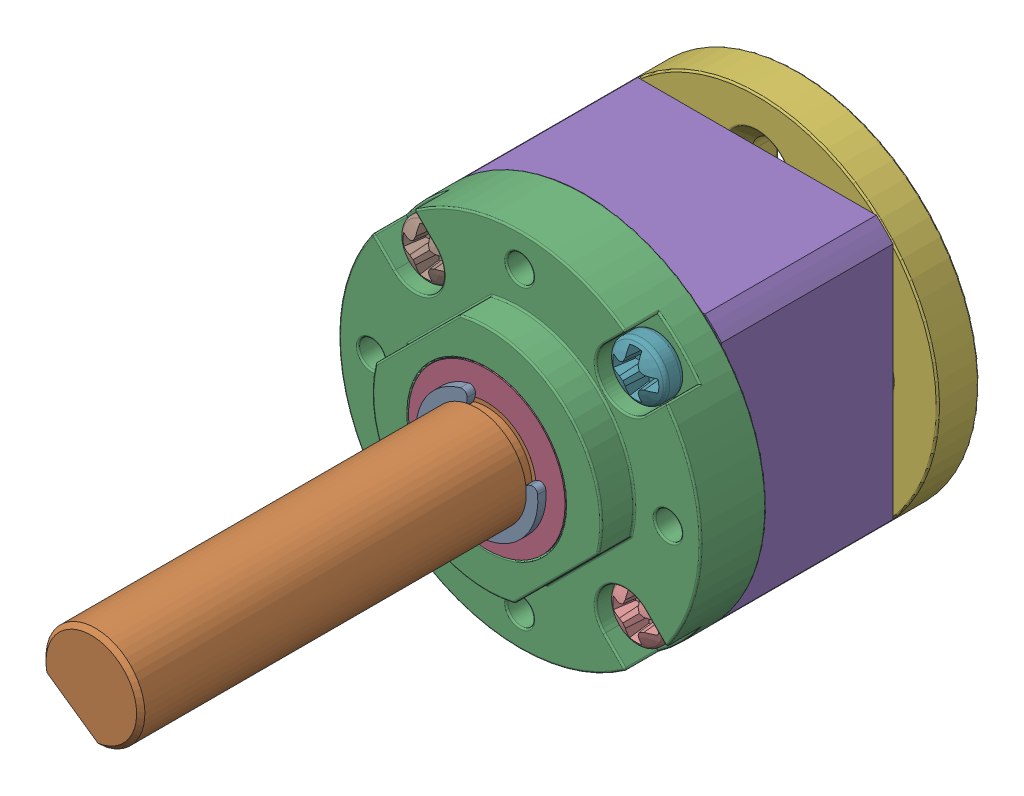
SolidWorks assembly DartBox V2 Drive 6mm Output.stp, configuration Default. Lengths in mm.
Overall size (21.95 21.95 42.9).
13 component instances, 7 part files, 0 mates.
Components (placement in the parent):
- Ring Gear.stp-1: Ring Gear.stp [Default] at (-10.101 0.0152 -54.1116) x (0 -1 0) z (0 0 1) size (21.95 21.95 40.4)
  - Front Plate.stp-1: Front Plate.stp [Default] at (0.0152 10.101 56.6116) x (0 1 0) z (1 0 0) size (21.95 30.5 21.95)
    - Shaft.stp-1: Shaft.stp [Default] x (-0.819152 0 -0.573576) z (0.573576 0 -0.819152) size (7.4 30.3 6.7)
      - Retaining Ring.stp-1: Retaining Ring.stp [Default] at (0 16.65 0) x (-1 0 0) z (0 -1 0) size (7.4 6.16 0.5)
      - Shaft-0.stp-1: Shaft-0.stp [Default] at origin size (6 30.3 6)
    - Front Plate-1.stp-1: Front Plate-1.stp [Default] at origin size (21.95 6.5 21.95)
    - Front Plate-2.stp-1: Front Plate-2.stp [Default] at origin size (9.5 6 9.5)
  - Ring Gear Body.stp-1: Ring Gear Body.stp [Default] at (0.0152 10.101 56.6116) x (0 1 0) z (1 0 0) size (16.5 10.4 16.5)
- Motor Mount Plate.stp-1: Motor Mount Plate.stp [Default] at (0 0 2.5) x (1 0 0) z (0 -1 0) size (21.95 3.5 21.95)
- Screws M2 x 14mm.stp-1: Screws M2 x 14mm.stp [Default] at (6.364 6.364 0.9) size (3.4 3.4 15.61)
- Screws M2 x 14mm.stp-2: Screws M2 x 14mm.stp [Default] at (-6.364 6.364 0.9) x (0 1 0) z (0 0 1) size (3.4 3.4 15.61)
- Screws M2 x 14mm.stp-3: Screws M2 x 14mm.stp [Default] at (-6.364 -6.364 0.9) x (-1 0 0) z (0 0 1) size (3.4 3.4 15.61)
- Screws M2 x 14mm.stp-4: Screws M2 x 14mm.stp [Default] at (6.364 -6.364 0.9) x (0 -1 0) z (0 0 1) size (3.4 3.4 15.61)
